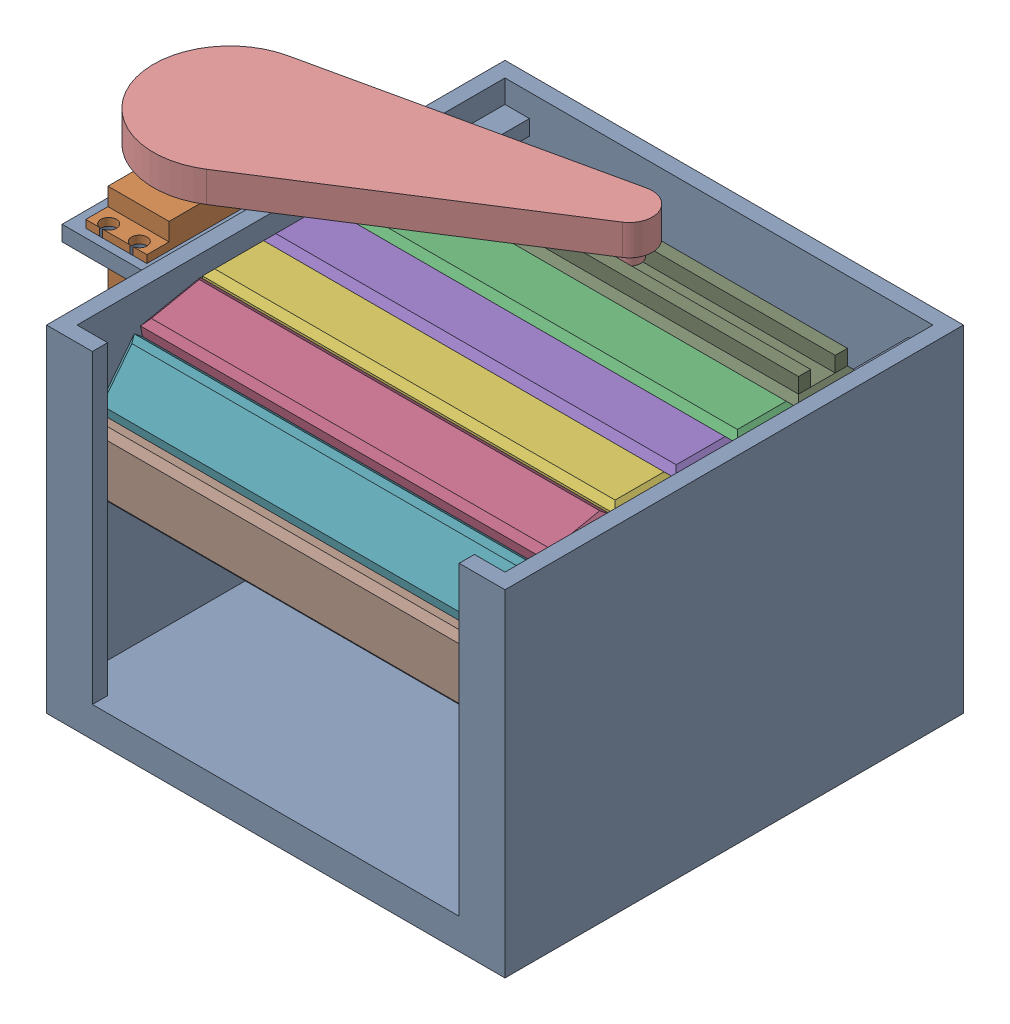
SolidWorks assembly garage, configuration Default. Lengths in mm.
Overall size (197.91 126.4 150).
10 component instances, 5 part files, 27 mates.
Components (placement in the parent):
- garage part-1: garage part [Default] at origin size (180 110 150)
- servo-1: servo [Default] at (-90 77.3 9.9) x (0 0 -1) z (1 0 0) size (54.5 44.1 20)
- door segment-1: door segment [Default] at (0 102.5 -18.5179) size (135 5.4 20)
- door segment-2: door segment [Default] at (0 100.5182 41.2837) x (1 0 0) z (0 -0.198181 0.980165) size (135 5.4 20)
- door segment-3: door segment [Default] at (0 102.5 1.4821) size (135 5.4 20)
- door segment-4: door segment [Default] at (0 102.5 21.4821) size (135 5.4 20)
- door segment-5: door segment [Default] at (0 90.6547 57.24) x (1 0 0) z (0 -0.788169 0.615459) size (135 5.4 20)
- door segment-6: door segment [Default] at (0 72.7912 63.9973) x (1 0 0) z (0 -0.998182 0.060272) size (135 5.4 20)
- last door segment 2-1: last door segment 2 [Default] at (0 102.5 -38.5179) size (135 10.4 20)
- link 2-2: link 2 [Default] at (-90 116.4 0) x (0.916489 0 -0.400061) z (0.400061 0 0.916489) size (132.5 15 50)
Mates (geometry in assembly coordinates):
- Parallel2: parallel anti-aligned: plane of garage part-1 through (-100 77.3 29.9) normal (0 1 0); plane of servo-1 through (-90 77.3 9.9) normal (0 -1 0)
- Parallel3: parallel anti-aligned: plane of garage part-1 through (-75 10 75) normal (-1 0 0); plane of servo-1 through (-80 106 29.9) normal (1 0 0)
- Coincident8: coincident anti-aligned: circle of garage part-1; circle of servo-1
- Coincident9: coincident anti-aligned: line of door segment-1 through (67.5 102.5 -28.5179) axis (-1 0 0); line of last door segment 2-1 through (-67.5 102.5 -28.5179) axis (1 0 0)
- Coincident10: coincident anti-aligned: line of door segment-1 through (-67.5 102.5 -8.5179) axis (1 0 0); line of door segment-3 through (67.5 102.5 -8.5179) axis (-1 0 0)
- Coincident11: coincident anti-aligned: line of door segment-3 through (-67.5 102.5 11.4821) axis (1 0 0); line of door segment-4 through (67.5 102.5 11.4821) axis (-1 0 0)
- Coincident12: coincident anti-aligned: line of door segment-2 through (67.5 102.5 31.4821) axis (-1 0 0); line of door segment-4 through (-67.5 102.5 31.4821) axis (1 0 0)
- Coincident13: coincident anti-aligned: line of door segment-2 through (-67.5 98.5364 51.0854) axis (1 0 0); line of door segment-5 through (67.5 98.5364 51.0854) axis (-1 0 0)
- Coincident14: coincident anti-aligned: line of door segment-5 through (-67.5 82.773 63.3946) axis (1 0 0); line of door segment-6 through (67.5 82.773 63.3946) axis (-1 0 0)
- Coincident15: coincident aligned: plane of door segment-1 through (-67.5 107.9 -8.5179) normal (-1 0 0); plane of last door segment 2-1 through (-67.5 107.9 -28.5179) normal (-1 0 0)
- Coincident16: coincident aligned: plane of door segment-3 through (-67.5 107.9 11.4821) normal (-1 0 0); plane of last door segment 2-1 through (-67.5 107.9 -28.5179) normal (-1 0 0)
- Coincident17: coincident aligned: plane of door segment-4 through (-67.5 107.9 31.4821) normal (-1 0 0); plane of last door segment 2-1 through (-67.5 107.9 -28.5179) normal (-1 0 0)
- Coincident18: coincident aligned: plane of door segment-2 through (-67.5 103.8293 52.1556) normal (-1 0 0); plane of last door segment 2-1 through (-67.5 107.9 -28.5179) normal (-1 0 0)
- Coincident19: coincident aligned: plane of door segment-5 through (-67.5 86.0965 67.6507) normal (-1 0 0); plane of last door segment 2-1 through (-67.5 107.9 -28.5179) normal (-1 0 0)
- Coincident20: coincident aligned: plane of door segment-6 through (-67.5 63.1348 69.9902) normal (-1 0 0); plane of last door segment 2-1 through (-67.5 107.9 -28.5179) normal (-1 0 0)
- Coincident21: coincident: point of door segment-6
- Coincident22: coincident: unknown of door segment-6
- Coincident23: coincident: unknown of door segment-2
- Coincident24: coincident: unknown of door segment-4
- Coincident25: coincident: unknown of door segment-3
- Coincident26: coincident: unknown of door segment-1
- Coincident27: coincident: unknown of door segment-1
- Coincident28: coincident: unknown of last door segment 2-1
- Parallel4: parallel anti-aligned: plane of servo-1 through (-90 114.3 9.9) normal (0 1 0); plane of link 2-2 through (2.4076 116.4 -38.2679) normal (0 -1 0)
- Concentric1: concentric anti-aligned: circle of servo-1; circle of link 2-2
- Coincident32: coincident anti-aligned: circle of servo-1; circle of link 2-2
- Tangent1: tangent anti-aligned: plane of last door segment 2-1 through (-65.5 112.9 -34.5179) normal (0 0 -1); cylinder of link 2-2 through (2.4076 111.4 -38.2679) axis (0 1 0) radius 3.75
